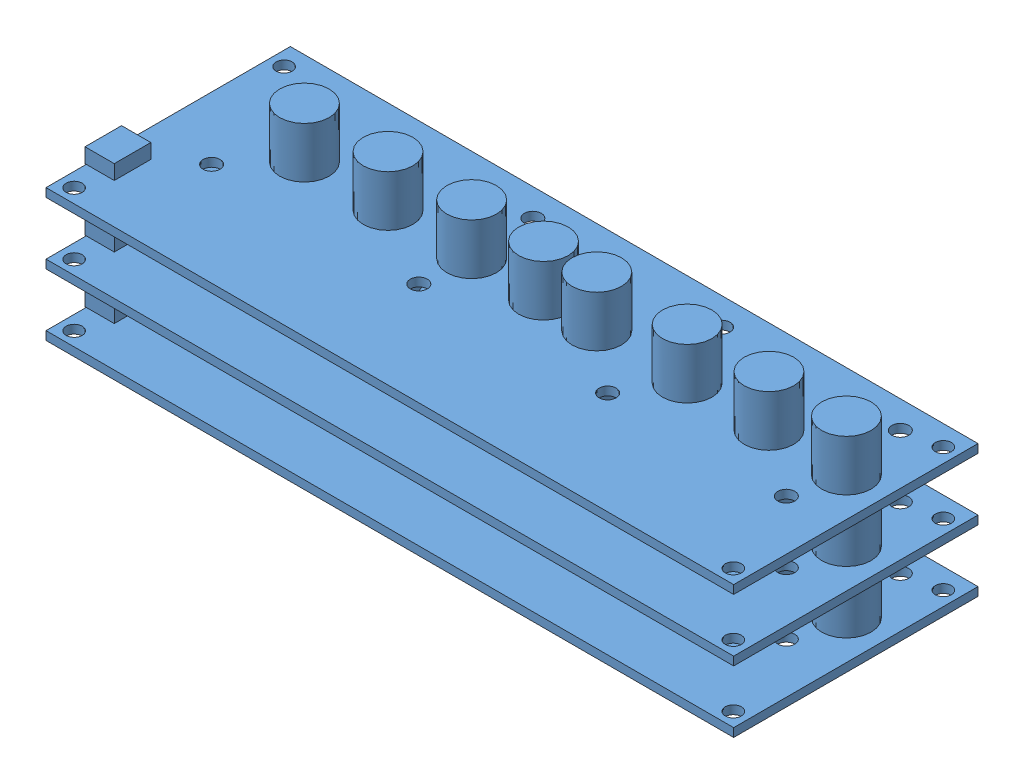
SolidWorks assembly odrive package, configuration Default. Lengths in mm.
Overall size (141.25 37.56 50.1).
3 component instances, 1 part files, 0 mates.
Components (placement in the parent):
- odrive-1: odrive [Default] at origin size (141.25 12.16 50.1)
- odrive-2: odrive [Default] at (0 12.7 0) size (141.25 12.16 50.1)
- odrive-3: odrive [Default] at (0 25.4 0) size (141.25 12.16 50.1)
